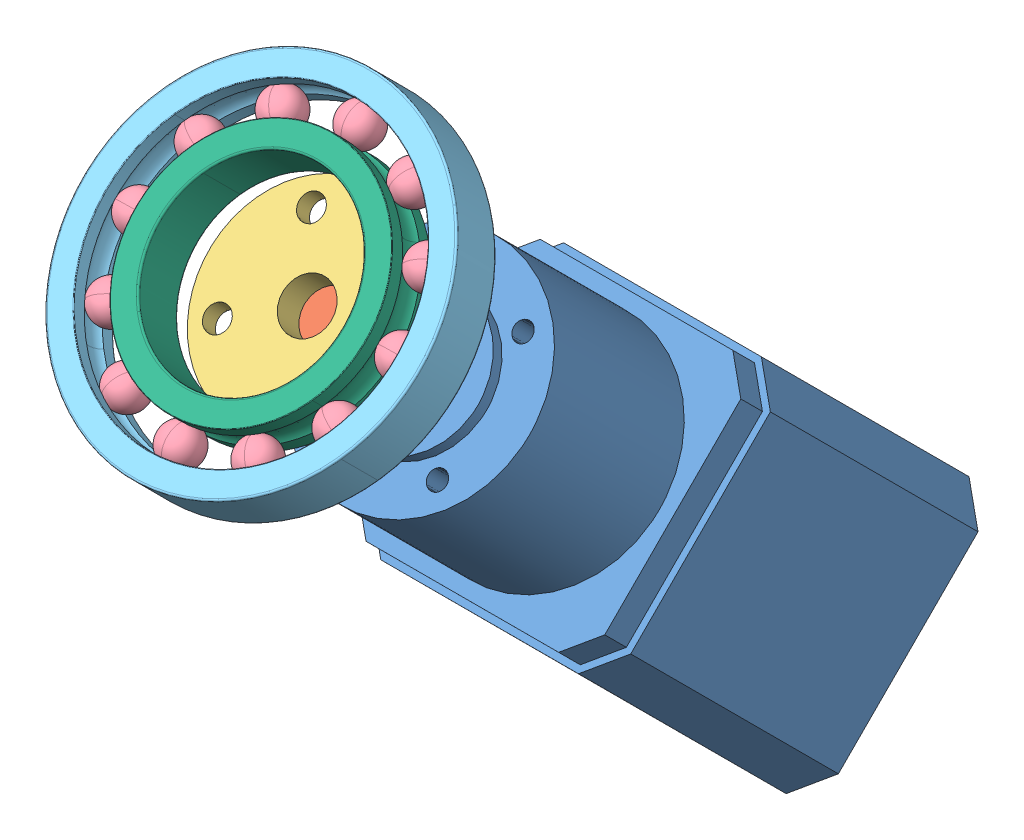
SolidWorks assembly assieme_Spalla_new, configuration Default. Lengths in mm.
Overall size (74.81 160.63 140.24).
20 component instances, 7 part files, 15 mates.
Components (placement in the parent):
- motore_spalla-1: motore_spalla [Default] at (7.2961 -48.9495 -116.1114) x (1 0.000382 -0.000382) z (0 0.707107 0.707107) size (42.3 42.3 104) (flexible)
  - 17HS19-1684S-PG14-1: 17HS19-1684S-PG14 [Default] at (-7.2931 5.4422 42.5) size (42.3 42.3 85)
  - albero_motore-1: albero_motore [Default] at (-7.2931 5.4422 127.5) x (0 0 1) z (-0.943838 0.330409 0) size (19 8 8)
- supporto_spalla_CHIUSO-1: supporto_spalla_CHIUSO [Default] x (1 0 0) z (0 -1 0) size (70 90.09 160.61)
- flangia_spalla-1: flangia_spalla [Default] at (0 62.0226 -12.8302) x (0.537947 -0.596076 0.596076) z (0 -0.707107 -0.707107) size (32 32 13)
- SKF_16006-1: SKF_16006 [Default] at (0 71.215 -3.6378) x (0 -0.707107 -0.707107) z (0.873766 -0.343899 0.343899) size (9 55 55)
  - SKF_16006_16-1: SKF_16006_16 [Default] x (1 0 0) z (0 -0.5 0.866025) size (6.35 6.35 6.35)
  - SKF_16006_16-2: SKF_16006_16 [Default] x (1 0 0) z (0 -0.866025 0.5) size (6.35 6.35 6.35)
  - SKF_16006_16-3: SKF_16006_16 [Default] x (1 0 0) z (0 -1 0) size (6.35 6.35 6.35)
  - SKF_16006_16-4: SKF_16006_16 [Default] x (1 0 0) z (0 -0.866025 -0.5) size (6.35 6.35 6.35)
  - SKF_16006_16-5: SKF_16006_16 [Default] x (1 0 0) z (0 -0.5 -0.866025) size (6.35 6.35 6.35)
  - SKF_16006_16-6: SKF_16006_16 [Default] x (1 0 0) z (0 0 -1) size (6.35 6.35 6.35)
  - SKF_16006_16-7: SKF_16006_16 [Default] x (1 0 0) z (0 0.5 -0.866025) size (6.35 6.35 6.35)
  - SKF_16006_16-8: SKF_16006_16 [Default] x (1 0 0) z (0 0.866025 -0.5) size (6.35 6.35 6.35)
  - SKF_16006_16-9: SKF_16006_16 [Default] x (1 0 0) z (0 1 0) size (6.35 6.35 6.35)
  - SKF_16006_16-10: SKF_16006_16 [Default] x (1 0 0) z (0 0.866025 0.5) size (6.35 6.35 6.35)
  - SKF_16006_16-11: SKF_16006_16 [Default] x (1 0 0) z (0 0.5 0.866025) size (6.35 6.35 6.35)
  - SKF_16006_16-12: SKF_16006_16 [Default] at origin size (6.35 6.35 6.35)
  - SKF_16006_29-1: SKF_16006_29 [Default] at origin size (9 55 55)
  - SKF_16006_31-1: SKF_16006_31 [Default] at origin size (9 37.7 37.7)
Mates (geometry in assembly coordinates):
- Coincidente1: coincident aligned: plane of supporto_spalla_CHIUSO-1 through (0 0 0) normal (0 0 1)
- Coincidente2: coincident anti-aligned: plane of supporto_spalla_CHIUSO-1 through (0 0 0) normal (0 -1 0)
- Coincidente3: coincident aligned: plane of supporto_spalla_CHIUSO-1 through (0 0 0) normal (1 0 0)
- Concentrico1: concentric aligned: cylinder of motore_spalla-1/17HS19-1684S-PG14-1 through (0 43.6378 -31.215) axis (0 -0.707107 -0.707107) radius 18; cylinder of supporto_spalla_CHIUSO-1 through (0 45.4056 -29.4472) axis (0 -0.707107 -0.707107) radius 11.1
- Concentrico2: concentric anti-aligned: circle of motore_spalla-1/17HS19-1684S-PG14-1; circle of supporto_spalla_NUOVO-1
- Coincidente4: coincident anti-aligned: plane of motore_spalla-1/17HS19-1684S-PG14-1 through (0 43.6378 -31.215) normal (0 0.707107 0.707107); plane of supporto_spalla_CHIUSO-1 through (20 57.78 -45.3571) normal (0 -0.707107 -0.707107)
- Concentrico4: concentric aligned: cylinder of motore_spalla-1/albero_motore-1 through (0 53.1838 -21.669) axis (0 -0.707107 -0.707107) radius 4; cylinder of flangia_spalla-1 through (0 60.6341 -14.2188) axis (0 -0.707107 -0.707107) radius 4
- Concentrico5: concentric aligned: cylinder of supporto_spalla_CHIUSO-1 through (0 71.215 -3.6378) axis (0 -0.707107 -0.707107) radius 27.575; cylinder of Bearig 8x22x7-1 through (0 72.9828 -1.8701) axis (0 -0.707107 -0.707107) radius 11
- Concentrico7: concentric aligned: cylinder of motore_spalla-1/albero_motore-1 through (0 58.4871 -16.3657) axis (0 -0.707107 -0.707107) radius 4; cylinder of Bearig 8x22x7-2 through (0 46.8198 -28.033) axis (0 -0.707107 -0.707107) radius 4
- Coincidente10: coincident anti-aligned: plane of supporto_spalla_NUOVO-1 through (0 41.8701 -32.9828) normal (0 0.707107 0.707107); plane of Bearig 8x22x7-2 through (0 41.8701 -32.9828) normal (0 -0.707107 -0.707107)
- Coincidente11: coincident anti-aligned: plane of supporto_spalla_NUOVO-1 through (0 69.0937 -5.7591) normal (0 -0.707107 -0.707107); plane of Bearig 8x22x7-1 through (0 72.9828 -1.8701) normal (0 0.707107 0.707107)
- Concentrico8: concentric anti-aligned: cylinder of motore_spalla-1/albero_motore-1 through (0 58.4871 -16.3657) axis (0 -0.707107 -0.707107) radius 4; cylinder of flangia_spalla-1 through (0 52.8302 -22.0226) axis (0 0.707107 0.707107) radius 8
- Concentrico9: concentric aligned: cylinder of supporto_spalla_CHIUSO-1 through (0 71.215 -3.6378) axis (0 -0.707107 -0.707107) radius 27.575; cylinder of SKF_16006-1/SKF_16006_29-1 through (0 35.8597 -38.9932) axis (0 -0.707107 -0.707107) radius 27.5
- Coincidente13: coincident anti-aligned: plane of supporto_spalla_CHIUSO-1 through (0 64.851 -10.0018) normal (0 0.707107 0.707107); plane of SKF_16006-1/SKF_16006_29-1 through (11.5507 79.5249 -24.6756) normal (0 -0.707107 -0.707107)
- Larghezza1: width anti-aligned: plane of supporto_spalla_CHIUSO-1 through (30 76.8718 -26.2652) normal (0 -0.707107 -0.707107); plane of supporto_spalla_CHIUSO-1 through (20 66.2652 -36.8718) normal (0 0.707107 0.707107); plane of flangia_spalla-1 through (0 62.0226 -12.8302) normal (0 0.707107 0.707107); plane of flangia_spalla-1 through (0 52.8302 -22.0226) normal (0 -0.707107 -0.707107)
